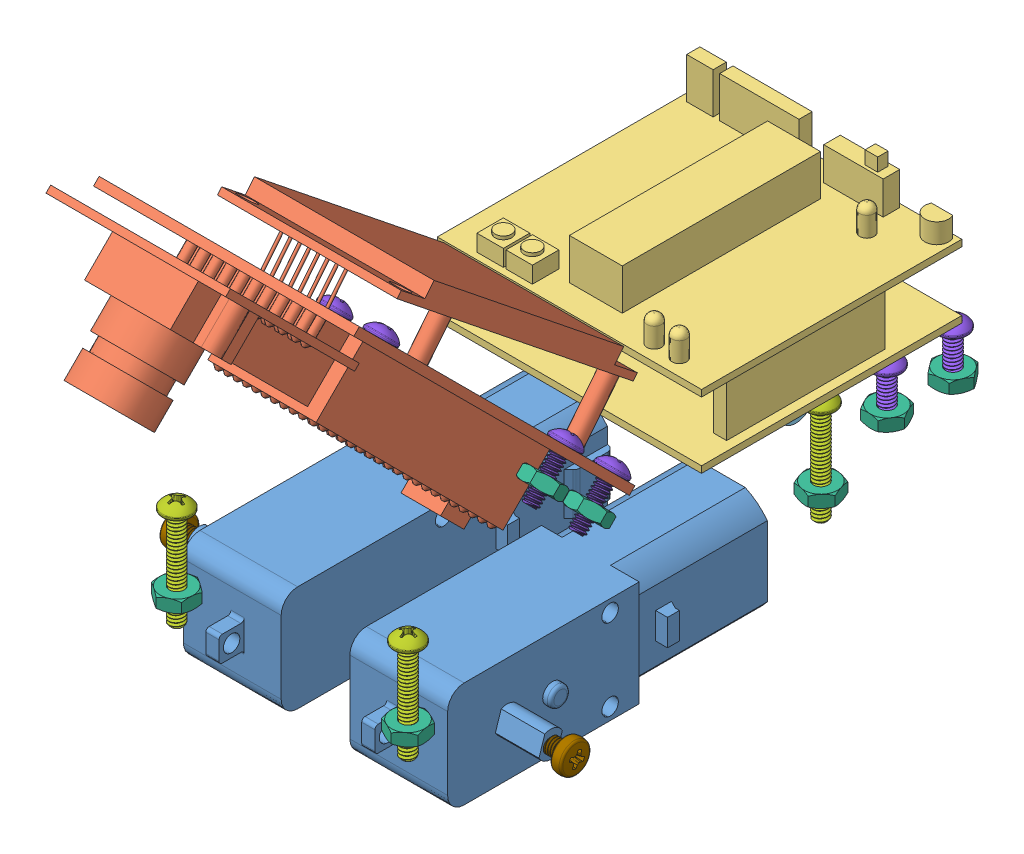
SolidWorks assembly Assembly, configuration Default. Lengths in mm.
Overall size (78.67 116.53 164.64).
47 component instances, 20 part files, 114 mates.
Components (placement in the parent):
- Motor Mount-1: Motor Mount [Default] at (3.175 15.875 -19.05) size (31.75 25.4 76.45) (hidden)
- Wheel 2in-1: Wheel 2in [Default] at (38.1 15.875 -19.05) x (1 0 0) z (0 0.586153 0.810201) size (15.88 53.2 53.2) (hidden)
- TT Motor-1: TT Motor [Default] at (6.604 15.875 -44.45) x (0 0 1) z (1 0 0) size (67.56 20.32 29.46)
- Chassis-1: Chassis [Default] at (3.175 5.3975 -6.35) x (0 0 1) z (-1 0 0) size (73.66 27.3 26.04) (hidden)
- Chassis-2: Chassis [Default] at (-3.175 26.3525 -6.35) x (0 0 1) z (1 0 0) size (73.66 27.3 26.04) (hidden)
- Motor Mount-2: Motor Mount [Default] at (-3.175 15.875 -19.05) x (-1 0 0) z (0 0 1) size (31.75 25.4 76.45) (hidden)
- TT Motor-2: TT Motor [Default] at (-6.604 15.875 -44.45) x (0 0 1) z (-1 0 0) size (67.56 20.32 29.46)
- Cap-1: Cap [Default] at (0 15.875 -76.2) x (0 0 1) z (-1 0 0) size (51.89 44.45 82.55) (hidden)
- Wheel 2in-2: Wheel 2in [Default] at (-38.1 15.875 -19.05) x (-1 0 0) z (0 0.586153 -0.810201) size (15.88 53.2 53.2) (hidden)
- Camera Board-1: Camera Board [Default] at (0 67.4784 -16.4528) x (-1 0 0) z (0 -0.707107 -0.707107) size (50.04 42.04 95)
- PIC Circuit-1: PIC Circuit [Default] at (0 38.1 -81.451) size (50.8 22.86 50.04)
- Front Cap-1: Front Cap [Default] at (0 15.875 -6.35) size (69.85 31.75 19.05) (hidden)
- Top Connector-1: Top Connector [Default] at (22.225 31.75 -82.55) x (0 0 -1) z (1 0 0) size (111.12 30.12 4.76) (hidden)
- Top Connector-2: Top Connector [Default] at (-22.225 31.75 -82.55) x (0 0 -1) z (1 0 0) size (111.12 30.12 4.76) (hidden)
- Tail-1: Tail [Default] at (0 15.875 -88.9) x (-1 0 0) z (0 0 -1) size (82.55 44.45 50.84) (hidden)
- Servo-1: Servo [Default] at (-32.258 16.7255 -105.9248) x (0 0.48481 -0.87462) z (0 -0.87462 -0.48481) size (32.26 29.72 12.19)
- Gear-1: Gear [Default] at (0 15.885 -88.9336) x (-1 0 0) z (0 -0.003163 -0.999995) size (41.34 35.83 44.49) (hidden)
- Servo Single Arm-1: Servo Single Arm [Default] at (-4.826 14.1395 -101.2596) x (0 -0.852015 -0.523518) z (0 -0.523518 0.852015) size (6.86 3.56 18.67)
- 90480A005_Low-Strength Steel Hex Nut-1: 90480A005_Low-Strength Steel Hex Nut [90480A005] at (-22.225 21.0344 -3.175) x (0.428518 0 0.903533) z (0.903533 0 -0.428518) size (6.35 2.87 7.33)
- 91772A113_Passivated 18-8 Stainless Steel Pan Head Phillips Screw-1: 91772A113_Passivated 18-8 Stainless Steel Pan Head Phillips Screw [91772A113] at (-22.225 26.3144 -3.175) x (-0.12802 0 0.991772) z (0 1 0) size (5.56 5.56 21.39)
- 90480A005_Low-Strength Steel Hex Nut-2: 90480A005_Low-Strength Steel Hex Nut [90480A005] at (22.225 21.0344 -3.175) x (0.591115 0 0.806587) z (0.806587 0 -0.591115) size (6.35 2.87 7.33)
- 91772A113_Passivated 18-8 Stainless Steel Pan Head Phillips Screw-2: 91772A113_Passivated 18-8 Stainless Steel Pan Head Phillips Screw [91772A113] at (22.225 26.416 -3.175) x (0.061178 0 0.998127) z (0 1 0) size (5.56 5.56 21.39)
- 91772A113_Passivated 18-8 Stainless Steel Pan Head Phillips Screw-4: 91772A113_Passivated 18-8 Stainless Steel Pan Head Phillips Screw [91772A113] at (22.225 26.416 -82.55) x (1 0 0) z (0 1 0) size (5.56 5.56 21.39)
- 90480A005_Low-Strength Steel Hex Nut-4: 90480A005_Low-Strength Steel Hex Nut [90480A005] at (22.225 21.0344 -82.55) x (0.732529 0 0.680736) z (0.680736 0 -0.732529) size (6.35 2.87 7.33)
- 90480A005_Low-Strength Steel Hex Nut-6: 90480A005_Low-Strength Steel Hex Nut [90480A005] at (-22.225 21.0344 -82.55) x (0.847691 0 0.53049) z (0.53049 0 -0.847691) size (6.35 2.87 7.33)
- 91772A113_Passivated 18-8 Stainless Steel Pan Head Phillips Screw-5: 91772A113_Passivated 18-8 Stainless Steel Pan Head Phillips Screw [91772A113] at (-22.225 26.416 -82.55) x (0.982082 0 -0.188455) z (0 1 0) size (5.56 5.56 21.39)
- 91772A108_Passivated 18-8 Stainless Steel Pan Head Phillips Screw-1: 91772A108_Passivated 18-8 Stainless Steel Pan Head Phillips Screw [91772A108] at (22.225 31.1785 -95.25) x (1 0 0) z (0 1 0) size (5.56 5.56 11.81)
- 90480A005_Low-Strength Steel Hex Nut-8: 90480A005_Low-Strength Steel Hex Nut [90480A005] at (22.225 27.3844 -95.25) x (0.829305 0 0.558796) z (0.558796 0 -0.829305) size (6.35 2.87 7.33)
- 91772A108_Passivated 18-8 Stainless Steel Pan Head Phillips Screw-2: 91772A108_Passivated 18-8 Stainless Steel Pan Head Phillips Screw [91772A108] at (22.225 31.1785 -107.95) x (0.982082 0 -0.188455) z (0 1 0) size (5.56 5.56 11.81)
- 90480A005_Low-Strength Steel Hex Nut-10: 90480A005_Low-Strength Steel Hex Nut [90480A005] at (22.225 27.3844 -107.95) x (0.919754 0 0.392496) z (0.392496 0 -0.919754) size (6.35 2.87 7.33)
- 91772A108_Passivated 18-8 Stainless Steel Pan Head Phillips Screw-4: 91772A108_Passivated 18-8 Stainless Steel Pan Head Phillips Screw [91772A108] at (-22.225 31.1785 -107.95) x (0.918365 0 -0.395734) z (0 1 0) size (5.56 5.56 11.81)
- 90480A005_Low-Strength Steel Hex Nut-12: 90480A005_Low-Strength Steel Hex Nut [90480A005] at (-22.225 27.3844 -107.95) x (0.98274 0 0.184994) z (0.184994 0 -0.98274) size (6.35 2.87 7.33)
- 91772A108_Passivated 18-8 Stainless Steel Pan Head Phillips Screw-6: 91772A108_Passivated 18-8 Stainless Steel Pan Head Phillips Screw [91772A108] at (-22.225 31.1785 -95.25) x (0.8 0 -0.6) z (0 1 0) size (5.56 5.56 11.81)
- 90480A005_Low-Strength Steel Hex Nut-14: 90480A005_Low-Strength Steel Hex Nut [90480A005] at (-22.225 27.3844 -95.25) x (0.998722 0 -0.050547) z (-0.050547 0 -0.998722) size (6.35 2.87 7.33)
- 91772A108_Passivated 18-8 Stainless Steel Pan Head Phillips Screw-8: 91772A108_Passivated 18-8 Stainless Steel Pan Head Phillips Screw [91772A108] at (22.225 50.1914 -30.5967) x (0.699365 -0.505415 -0.505415) z (0 0.707107 -0.707107) size (5.56 5.56 11.81)
- 90480A005_Low-Strength Steel Hex Nut-16: 90480A005_Low-Strength Steel Hex Nut [90480A005] at (22.225 48.676 -29.0813) x (0.979395 -0.142805 -0.142805) z (-0.201956 -0.692537 -0.692537) size (6.35 2.87 7.33)
- 91772A108_Passivated 18-8 Stainless Steel Pan Head Phillips Screw-10: 91772A108_Passivated 18-8 Stainless Steel Pan Head Phillips Screw [91772A108] at (22.225 41.2112 -39.5769) x (0.683739 -0.515995 -0.515995) z (0 0.707107 -0.707107) size (5.56 5.56 11.81)
- 90480A005_Low-Strength Steel Hex Nut-18: 90480A005_Low-Strength Steel Hex Nut [90480A005] at (22.225 39.6958 -38.0615) x (0.974797 -0.157752 -0.157752) z (-0.223096 -0.689285 -0.689285) size (6.35 2.87 7.33)
- 91772A108_Passivated 18-8 Stainless Steel Pan Head Phillips Screw-12: 91772A108_Passivated 18-8 Stainless Steel Pan Head Phillips Screw [91772A108] at (-22.225 50.1914 -30.5967) x (0.634301 -0.546654 -0.546654) z (0 0.707107 -0.707107) size (5.56 5.56 11.81)
- 90480A005_Low-Strength Steel Hex Nut-20: 90480A005_Low-Strength Steel Hex Nut [90480A005] at (-22.225 48.676 -29.0813) x (0.958027 -0.202713 -0.202713) z (-0.286679 -0.677427 -0.677427) size (6.35 2.87 7.33)
- 91772A108_Passivated 18-8 Stainless Steel Pan Head Phillips Screw-14: 91772A108_Passivated 18-8 Stainless Steel Pan Head Phillips Screw [91772A108] at (-22.225 41.2112 -39.5769) x (0.544611 -0.593043 -0.593043) z (0 0.707107 -0.707107) size (5.56 5.56 11.81)
- 90480A005_Low-Strength Steel Hex Nut-22: 90480A005_Low-Strength Steel Hex Nut [90480A005] at (-22.225 39.6958 -38.0615) x (0.920304 -0.276622 -0.276622) z (-0.391203 -0.650753 -0.650753) size (6.35 2.87 7.33)
- 92005A118_Steel Pan Head Phillips Screw-1: 92005A118_Steel Pan Head Phillips Screw [92005A118] at (-32.5125 15.875 -19.05) x (0 0.980077 0.198616) z (-1 0 0) size (6 6 10.57)
- 92005A118_Steel Pan Head Phillips Screw-2: 92005A118_Steel Pan Head Phillips Screw [92005A118] at (32.5125 15.875 -19.05) x (0 -0.392368 -0.919808) z (1 0 0) size (6 6 10.57)
- 91772A086_Passivated 18-8 Stainless Steel Pan Head Phillips Screw-1: 91772A086_Passivated 18-8 Stainless Steel Pan Head Phillips Screw [91772A086] at (-25.9499 9.8763 -93.6036) x (0 -0.608635 -0.79345) z (1 0 0) size (4.24 4.24 27.29)
- 90480A003_Low-Strength Steel Hex Nut-1: 90480A003_Low-Strength Steel Hex Nut [90480A003] at (-23.6538 9.8763 -93.6036) x (0 0.999076 -0.042978) z (0 0.042978 0.999076) size (4.76 1.94 5.5)
- Head-1: Head [Default] at (0 15.875 0) size (69.85 34.93 34.93) (hidden)
Mates (geometry in assembly coordinates):
- Concentric1: concentric anti-aligned: cylinder of Motor Mount-1 through (34.925 15.875 -19.05) axis (-1 0 0) radius 5.3975; cylinder of Wheel 2in-1 through (25.4 15.875 -19.05) axis (1 0 0) radius 4.7625
- Distance1: distance = 3.175 mm anti-aligned: plane of Wheel 2in-1 through (38.1 15.875 -19.05) normal (-1 0 0); plane of Motor Mount-1 through (34.925 15.875 -19.05) normal (1 0 0)
- Coincident2: coincident anti-aligned: plane of Wheel 2in-1 through (25.4 17.053 -21.3003) normal (0 0.308058 0.951368); plane of TT Motor-1 through (33.782 13.6016 -20.1827) normal (0 -0.308058 -0.951368)
- Concentric3: concentric anti-aligned: cylinder of Wheel 2in-1 through (25.4 15.875 -19.05) axis (1 0 0) radius 2.54; cylinder of TT Motor-1 through (33.782 15.875 -19.05) axis (-1 0 0) radius 2.54
- Parallel1: parallel aligned: plane of Motor Mount-1 through (34.925 28.575 -6.35) normal (0 1 0); plane of TT Motor-1 through (25.4 26.035 -44.45) normal (0 1 0)
- Coincident4: coincident anti-aligned: plane of Wheel 2in-1 through (25.4 15.875 -19.05) normal (-1 0 0); plane of TT Motor-1 through (25.4 15.875 -44.45) normal (1 0 0)
- Coincident5: coincident anti-aligned: plane of Motor Mount-1 through (26.035 15.875 -19.05) normal (-1 0 0); plane of Chassis-1 through (26.035 5.3975 -6.35) normal (1 0 0)
- Concentric4: concentric anti-aligned: cylinder of Motor Mount-1 through (34.925 22.225 -73.025) axis (-1 0 0) radius 1.5875; cylinder of Chassis-1 through (0 22.225 -73.025) axis (1 0 0) radius 1.5875
- Concentric5: concentric anti-aligned: cylinder of Motor Mount-1 through (34.925 9.525 -73.025) axis (-1 0 0) radius 1.5875; cylinder of Chassis-1 through (0 9.525 -73.025) axis (1 0 0) radius 1.5875
- Concentric6: concentric anti-aligned: cylinder of Chassis-1 through (0 9.525 -73.025) axis (1 0 0) radius 1.5875; cylinder of Chassis-2 through (0 9.525 -73.025) axis (-1 0 0) radius 1.5875
- Concentric7: concentric anti-aligned: cylinder of Chassis-1 through (0 22.225 -73.025) axis (1 0 0) radius 1.5875; cylinder of Chassis-2 through (0 22.225 -73.025) axis (-1 0 0) radius 1.5875
- Coincident7: coincident anti-aligned: plane of Chassis-1 through (0 5.3975 -6.35) normal (-1 0 0); plane of Chassis-2 through (0 26.3525 -6.35) normal (1 0 0)
- Concentric8: concentric anti-aligned: cylinder of Chassis-2 through (0 22.225 -73.025) axis (-1 0 0) radius 1.5875; cylinder of Motor Mount-2 through (-34.925 22.225 -73.025) axis (1 0 0) radius 1.5875
- Concentric9: concentric anti-aligned: cylinder of Chassis-2 through (0 9.525 -73.025) axis (-1 0 0) radius 1.5875; cylinder of Motor Mount-2 through (-34.925 9.525 -73.025) axis (1 0 0) radius 1.5875
- Coincident8: coincident anti-aligned: plane of Chassis-2 through (-3.175 26.3525 -6.35) normal (-1 0 0); plane of Motor Mount-2 through (-3.175 15.875 -19.05) normal (1 0 0)
- Concentric10: concentric aligned: cylinder of Motor Mount-2 through (-34.925 15.875 -19.05) axis (1 0 0) radius 5.3975; cylinder of TT Motor-2 through (-33.782 15.875 -19.05) axis (1 0 0) radius 2.54
- Parallel2: parallel aligned: plane of Motor Mount-2 through (-34.925 28.575 -6.35) normal (0 1 0); plane of TT Motor-2 through (-25.4 26.035 -44.45) normal (0 1 0)
- Coincident11: coincident anti-aligned: plane of Chassis-2 through (-3.175 26.3525 -6.35) normal (-1 0 0); plane of Cap-1 through (-3.175 15.875 -63.5) normal (1 0 0)
- Coincident12: coincident anti-aligned: plane of Chassis-2 through (-3.175 29.5275 -6.35) normal (0 1 0); plane of Cap-1 through (0 29.5275 -63.5) normal (0 -1 0)
- Coincident13: coincident anti-aligned: plane of Motor Mount-2 through (-34.925 3.175 -76.2) normal (0 0 -1); plane of Cap-1 through (0 15.875 -76.2) normal (0 0 1)
- Coincident14: coincident anti-aligned: plane of TT Motor-2 through (-33.782 18.1484 -20.1827) normal (0 0.308058 -0.951368); plane of Wheel 2in-2 through (-25.4 14.697 -21.3003) normal (0 -0.308058 0.951368)
- Concentric11: concentric anti-aligned: cylinder of Motor Mount-2 through (-34.925 15.875 -19.05) axis (1 0 0) radius 5.3975; cylinder of Wheel 2in-2 through (-25.4 15.875 -19.05) axis (-1 0 0) radius 4.7625
- Coincident15: coincident anti-aligned: plane of TT Motor-2 through (-25.4 15.875 -44.45) normal (-1 0 0); plane of Wheel 2in-2 through (-25.4 15.875 -19.05) normal (1 0 0)
- Coincident16: coincident: line of Chassis-1 through (0 22.479 -6.35) axis (0 1 0)
- Coincident17: coincident anti-aligned: plane of Camera Board-1 through (0 67.4784 -16.4528) normal (-1 0 0)
- Coincident18: coincident aligned: plane of PIC Circuit-1 through (0 38.1 -81.451) normal (1 0 0)
- Distance2: distance = 3.175 mm anti-aligned: plane of Motor Mount-2 through (-34.925 15.875 -19.05) normal (-1 0 0); plane of Wheel 2in-2 through (-38.1 15.875 -19.05) normal (1 0 0)
- Coincident19: coincident anti-aligned: plane of Motor Mount-1 through (34.925 28.575 -6.35) normal (0 0 1); plane of Front Cap-1 through (0 15.875 -6.35) normal (0 0 -1)
- Coincident20: coincident anti-aligned: plane of Chassis-1 through (3.175 5.3975 -6.35) normal (1 0 0); plane of Front Cap-1 through (3.175 15.875 -19.05) normal (-1 0 0)
- Coincident21: coincident anti-aligned: plane of Chassis-1 through (3.175 2.2225 -6.35) normal (0 -1 0); plane of Front Cap-1 through (0 2.2225 -19.05) normal (0 1 0)
- Concentric12: concentric anti-aligned: cylinder of Cap-1 through (22.225 11.43 -82.55) axis (0 1 0) radius 1.5875; cylinder of Top Connector-1 through (22.225 34.925 -82.55) axis (0 -1 0) radius 1.5875
- Concentric13: concentric anti-aligned: cylinder of Front Cap-1 through (22.225 11.43 -3.175) axis (0 1 0) radius 1.5875; cylinder of Top Connector-1 through (22.225 34.925 -3.175) axis (0 -1 0) radius 1.5875
- Coincident22: coincident anti-aligned: plane of Front Cap-1 through (0 31.75 -19.05) normal (0 1 0); plane of Top Connector-1 through (22.225 31.75 -82.55) normal (0 -1 0)
- Concentric14: concentric anti-aligned: cylinder of Camera Board-1 through (22.225 52.8406 -33.2459) axis (0 -0.707107 0.707107) radius 1.651; cylinder of Top Connector-1 through (22.225 25.6714 -6.0766) axis (0 0.707107 -0.707107) radius 1.5875
- Concentric15: concentric anti-aligned: cylinder of Camera Board-1 through (22.225 43.8604 -42.2261) axis (0 -0.707107 0.707107) radius 1.651; cylinder of Top Connector-1 through (22.225 16.6911 -15.0569) axis (0 0.707107 -0.707107) radius 1.5875
- Coincident23: coincident anti-aligned: plane of Camera Board-1 through (0 67.4784 -16.4528) normal (0 -0.707107 0.707107); plane of Top Connector-1 through (19.8438 16.5656 -67.3656) normal (0 0.707107 -0.707107)
- Concentric16: concentric anti-aligned: cylinder of Cap-1 through (-22.225 11.43 -82.55) axis (0 1 0) radius 1.5875; cylinder of Top Connector-2 through (-22.225 34.925 -82.55) axis (0 -1 0) radius 1.5875
- Concentric17: concentric anti-aligned: cylinder of Front Cap-1 through (-22.225 11.43 -3.175) axis (0 1 0) radius 1.5875; cylinder of Top Connector-2 through (-22.225 34.925 -3.175) axis (0 -1 0) radius 1.5875
- Coincident24: coincident anti-aligned: plane of Cap-1 through (0 31.75 -63.5) normal (0 1 0); plane of Top Connector-2 through (-22.225 31.75 -82.55) normal (0 -1 0)
- Coincident25: coincident anti-aligned: plane of Cap-1 through (0 15.875 -88.9) normal (0 0 -1); plane of Tail-1 through (0 15.875 -88.9) normal (0 0 1)
- Coincident26: coincident aligned: plane of Cap-1 through (-41.275 15.875 -76.2) normal (-1 0 0); plane of Tail-1 through (-41.275 -6.35 -88.9) normal (-1 0 0)
- Tangent1: tangent: line of Cap-1 through (-34.925 31.75 -88.9) axis (1 0 0); face of Tail-1
- Coincident27: coincident anti-aligned: plane of Front Cap-1 through (0 0 0) normal (0 -1 0)
- Coincident28: coincident aligned: plane of Front Cap-1 through (0 15.875 0) normal (0 0 1)
- Coincident30: coincident anti-aligned: plane of Tail-1 through (-16.51 4.3712 -99.7044) normal (0 0.48481 -0.87462); plane of Servo-1 through (-9.906 5.8524 -98.8833) normal (0 -0.48481 0.87462)
- Coincident31: coincident anti-aligned: plane of Tail-1 through (-16.51 16.5158 -92.9725) normal (0 -0.87462 -0.48481); plane of Servo-1 through (-9.906 16.5158 -92.9725) normal (0 0.87462 0.48481)
- Coincident32: coincident anti-aligned: plane of Tail-1 through (-16.51 15.875 -88.9) normal (1 0 0); plane of Servo-1 through (-16.51 9.8763 -93.6036) normal (-1 0 0)
- Concentric18: concentric aligned: cylinder of Tail-1 through (-41.2761 5.2681 -92.075) axis (1 0 0) radius 1.5875; cylinder of Gear-1 through (-41.2761 5.2681 -92.075) axis (1 0 0) radius 1.5875
- Coincident33: coincident anti-aligned: plane of Tail-1 through (-3.175 -3.175 -139.7) normal (1 0 0); plane of Gear-1 through (-3.175 -3.3256 -139.6731) normal (-1 0 0)
- Concentric19: concentric aligned: cylinder of Servo-1 through (-2.54 14.1395 -101.2596) axis (-1 0 0) radius 2.413; cylinder of Servo Single Arm-1 through (-1.27 14.1395 -101.2596) axis (-1 0 0) radius 2.286
- Coincident34: coincident anti-aligned: plane of Servo-1 through (-2.54 14.1395 -101.2596) normal (1 0 0); plane of Servo Single Arm-1 through (-2.54 14.1395 -101.2596) normal (-1 0 0)
- Distance3: distance = 9.525 mm: cylinder of Gear-1 through (0 12.656 -109.5102) axis (1 0 0) radius 0.8047; cylinder of Servo Single Arm-1 through (-4.826 21.4531 -113.1623) axis (1 0 0) radius 0.508
- Coincident35: coincident anti-aligned: plane of PIC Circuit-1 through (0 38.1 -81.451) normal (0 -1 0); plane of Top Connector-1 through (19.8438 38.1 -82.55) normal (0 1 0)
- Coincident36: coincident anti-aligned: plane of PIC Circuit-1 through (-25.4 39.37 -56.432) normal (0 0 1); plane of Top Connector-1 through (19.8438 31.75 -56.432) normal (0 0 -1)
- Concentric21: concentric anti-aligned: cylinder of Top Connector-2 through (-22.225 34.925 -3.175) axis (0 -1 0) radius 1.5875; cylinder of 91772A110_Passivated 18-8 Stainless Steel Pan Head Phillips Screw-1 through (-22.225 37.0313 -3.175) axis (0 1 0) radius 1.4224
- Coincident38: coincident anti-aligned: plane of Front Cap-1 through (-26.1937 22.225 -6.35) normal (0 -1 0); plane of 90480A005_Low-Strength Steel Hex Nut-1 through (-25.2418 22.225 -5.2582) normal (0 1 0)
- Concentric22: concentric anti-aligned: cylinder of Top Connector-2 through (-22.225 34.925 -3.175) axis (0 -1 0) radius 1.5875; cylinder of 91772A113_Passivated 18-8 Stainless Steel Pan Head Phillips Screw-1 through (-22.225 36.8554 -3.175) axis (0 1 0) radius 1.4224
- Tangent2: tangent anti-aligned: plane of Top Connector-2 through (-22.225 34.925 -82.55) normal (0 1 0); torus of 91772A113_Passivated 18-8 Stainless Steel Pan Head Phillips Screw-1
- Concentric23: concentric aligned: cylinder of 90480A005_Low-Strength Steel Hex Nut-1 through (-22.225 19.8438 -3.175) axis (0 1 0) radius 1.4224; cylinder of 91772A113_Passivated 18-8 Stainless Steel Pan Head Phillips Screw-1 through (-22.225 36.8554 -3.175) axis (0 1 0) radius 1.4224
- Concentric24: concentric aligned: cylinder of 90480A005_Low-Strength Steel Hex Nut-2 through (22.225 19.8438 -3.175) axis (0 1 0) radius 1.4224; cylinder of 91772A113_Passivated 18-8 Stainless Steel Pan Head Phillips Screw-2 through (22.225 36.957 -3.175) axis (0 1 0) radius 1.4224
- Coincident39: coincident anti-aligned: plane of Front Cap-1 through (26.1937 22.225 -6.35) normal (0 -1 0); plane of 90480A005_Low-Strength Steel Hex Nut-2 through (18.8697 22.225 -4.6523) normal (0 1 0)
- Concentric25: concentric anti-aligned: cylinder of Top Connector-1 through (22.225 34.925 -3.175) axis (0 -1 0) radius 1.5875; cylinder of 91772A113_Passivated 18-8 Stainless Steel Pan Head Phillips Screw-2 through (22.225 36.957 -3.175) axis (0 1 0) radius 1.4224
- Coincident40: coincident anti-aligned: plane of Top Connector-1 through (22.225 34.925 -82.55) normal (0 1 0); plane of 91772A113_Passivated 18-8 Stainless Steel Pan Head Phillips Screw-2 through (23.6447 34.925 -3.262) normal (0 -1 0)
- Coincident41: coincident anti-aligned: plane of Top Connector-1 through (22.225 34.925 -82.55) normal (0 1 0); plane of 91772A113_Passivated 18-8 Stainless Steel Pan Head Phillips Screw-4 through (22.225 34.925 -83.9724) normal (0 -1 0)
- Concentric27: concentric anti-aligned: cylinder of Top Connector-1 through (22.225 34.925 -82.55) axis (0 -1 0) radius 1.5875; cylinder of 91772A113_Passivated 18-8 Stainless Steel Pan Head Phillips Screw-4 through (22.225 36.957 -82.55) axis (0 1 0) radius 1.4224
- Concentric28: concentric aligned: cylinder of 91772A113_Passivated 18-8 Stainless Steel Pan Head Phillips Screw-4 through (22.225 36.957 -82.55) axis (0 1 0) radius 1.4224; cylinder of 90480A005_Low-Strength Steel Hex Nut-4 through (22.225 19.8438 -82.55) axis (0 1 0) radius 1.4224
- Coincident42: coincident anti-aligned: plane of Cap-1 through (26.1937 22.225 -76.2) normal (0 -1 0); plane of 90480A005_Low-Strength Steel Hex Nut-4 through (18.6514 22.225 -83.3685) normal (0 1 0)
- Concentric29: concentric aligned: cylinder of 90480A005_Low-Strength Steel Hex Nut-6 through (-22.225 19.8438 -82.55) axis (0 1 0) radius 1.4224; cylinder of 91772A113_Passivated 18-8 Stainless Steel Pan Head Phillips Screw-5 through (-22.225 36.957 -82.55) axis (0 1 0) radius 1.4224
- Coincident43: coincident anti-aligned: plane of Top Connector-2 through (-22.225 34.925 -82.55) normal (0 1 0); plane of 91772A113_Passivated 18-8 Stainless Steel Pan Head Phillips Screw-5 through (-22.4931 34.925 -83.9469) normal (0 -1 0)
- Concentric30: concentric anti-aligned: cylinder of Top Connector-2 through (-22.225 34.925 -82.55) axis (0 -1 0) radius 1.5875; cylinder of 91772A113_Passivated 18-8 Stainless Steel Pan Head Phillips Screw-5 through (-22.225 36.957 -82.55) axis (0 1 0) radius 1.4224
- Coincident44: coincident anti-aligned: plane of Cap-1 through (-26.1937 22.225 -76.2) normal (0 -1 0); plane of 90480A005_Low-Strength Steel Hex Nut-6 through (-25.8889 22.225 -82.6804) normal (0 1 0)
- Coincident45: coincident anti-aligned: plane of Top Connector-1 through (22.225 34.925 -82.55) normal (0 1 0); plane of 91772A108_Passivated 18-8 Stainless Steel Pan Head Phillips Screw-1 through (22.225 34.925 -96.6724) normal (0 -1 0)
- Concentric32: concentric aligned: cylinder of Top Connector-1 through (22.225 31.75 -95.25) axis (0 1 0) radius 1.5875; cylinder of 91772A108_Passivated 18-8 Stainless Steel Pan Head Phillips Screw-1 through (22.225 36.957 -95.25) axis (0 1 0) radius 1.4224
- Concentric33: concentric aligned: cylinder of 91772A108_Passivated 18-8 Stainless Steel Pan Head Phillips Screw-1 through (22.225 36.957 -95.25) axis (0 1 0) radius 1.4224; cylinder of 90480A005_Low-Strength Steel Hex Nut-8 through (22.225 26.1937 -95.25) axis (0 1 0) radius 1.4224
- Tangent7: tangent: plane of assembly; face of Tail-1; plane of 90480A005_Low-Strength Steel Hex Nut-8 through (18.5676 28.575 -95.504) normal (0 1 0)
- Concentric34: concentric aligned: cylinder of 91772A108_Passivated 18-8 Stainless Steel Pan Head Phillips Screw-2 through (22.225 36.957 -107.95) axis (0 1 0) radius 1.4224; cylinder of 90480A005_Low-Strength Steel Hex Nut-10 through (22.225 26.1937 -107.95) axis (0 1 0) radius 1.4224
- Coincident47: coincident anti-aligned: plane of Top Connector-1 through (22.225 34.925 -82.55) normal (0 1 0); plane of 91772A108_Passivated 18-8 Stainless Steel Pan Head Phillips Screw-2 through (21.9569 34.925 -109.3469) normal (0 -1 0)
- Concentric35: concentric aligned: cylinder of Top Connector-1 through (22.225 31.75 -107.95) axis (0 1 0) radius 1.5875; cylinder of 91772A108_Passivated 18-8 Stainless Steel Pan Head Phillips Screw-2 through (22.225 36.957 -107.95) axis (0 1 0) radius 1.4224
- Tangent8: tangent: plane of assembly; face of Tail-1; plane of 90480A005_Low-Strength Steel Hex Nut-10 through (18.5853 28.575 -107.5102) normal (0 1 0)
- Concentric37: concentric aligned: cylinder of 91772A108_Passivated 18-8 Stainless Steel Pan Head Phillips Screw-4 through (-22.225 36.957 -107.95) axis (0 1 0) radius 1.4224; cylinder of 90480A005_Low-Strength Steel Hex Nut-12 through (-22.225 26.1937 -107.95) axis (0 1 0) radius 1.4224
- Coincident48: coincident anti-aligned: plane of Top Connector-2 through (-22.225 34.925 -82.55) normal (0 1 0); plane of 91772A108_Passivated 18-8 Stainless Steel Pan Head Phillips Screw-4 through (-22.7879 34.925 -109.2563) normal (0 -1 0)
- Concentric38: concentric aligned: cylinder of Top Connector-2 through (-22.225 31.75 -107.95) axis (0 1 0) radius 1.5875; cylinder of 91772A108_Passivated 18-8 Stainless Steel Pan Head Phillips Screw-4 through (-22.225 36.957 -107.95) axis (0 1 0) radius 1.4224
- Tangent9: tangent: plane of assembly; face of Tail-1; plane of 90480A005_Low-Strength Steel Hex Nut-12 through (-25.6843 28.575 -106.7359) normal (0 1 0)
- Concentric40: concentric aligned: cylinder of 91772A108_Passivated 18-8 Stainless Steel Pan Head Phillips Screw-6 through (-22.225 36.957 -95.25) axis (0 1 0) radius 1.4224; cylinder of 90480A005_Low-Strength Steel Hex Nut-14 through (-22.225 26.1937 -95.25) axis (0 1 0) radius 1.4224
- Coincident49: coincident anti-aligned: plane of Top Connector-2 through (-22.225 34.925 -82.55) normal (0 1 0); plane of 91772A108_Passivated 18-8 Stainless Steel Pan Head Phillips Screw-6 through (-23.0784 34.925 -96.3879) normal (0 -1 0)
- Concentric41: concentric aligned: cylinder of Top Connector-2 through (-22.225 31.75 -95.25) axis (0 1 0) radius 1.5875; cylinder of 91772A108_Passivated 18-8 Stainless Steel Pan Head Phillips Screw-6 through (-22.225 36.957 -95.25) axis (0 1 0) radius 1.4224
- Tangent10: tangent: plane of assembly; face of Tail-1; plane of 90480A005_Low-Strength Steel Hex Nut-14 through (-25.3033 28.575 -93.2588) normal (0 1 0)
- Concentric43: concentric aligned: cylinder of 91772A108_Passivated 18-8 Stainless Steel Pan Head Phillips Screw-8 through (22.225 54.2775 -34.6827) axis (0 0.707107 -0.707107) radius 1.4224; cylinder of 90480A005_Low-Strength Steel Hex Nut-16 through (22.225 47.8341 -28.2394) axis (0 0.707107 -0.707107) radius 1.4224
- Coincident50: coincident anti-aligned: plane of Camera Board-1 through (0 68.5561 -17.5304) normal (0 0.707107 -0.707107); plane of 91772A108_Passivated 18-8 Stainless Steel Pan Head Phillips Screw-8 through (21.2083 52.1372 -33.9493) normal (0 -0.707107 0.707107)
- Concentric44: concentric anti-aligned: cylinder of Camera Board-1 through (22.225 52.8406 -33.2459) axis (0 -0.707107 0.707107) radius 1.651; cylinder of 91772A108_Passivated 18-8 Stainless Steel Pan Head Phillips Screw-8 through (22.225 54.2775 -34.6827) axis (0 0.707107 -0.707107) radius 1.4224
- Coincident51: coincident anti-aligned: plane of Top Connector-1 through (19.8438 14.3205 -65.1205) normal (0 -0.707107 0.707107); plane of 90480A005_Low-Strength Steel Hex Nut-16 through (19.4856 51.2408 -28.2003) normal (0 0.707107 -0.707107)
- Concentric46: concentric aligned: cylinder of 91772A108_Passivated 18-8 Stainless Steel Pan Head Phillips Screw-10 through (22.225 45.2972 -43.663) axis (0 0.707107 -0.707107) radius 1.4224; cylinder of 90480A005_Low-Strength Steel Hex Nut-18 through (22.225 38.8539 -37.2196) axis (0 0.707107 -0.707107) radius 1.4224
- Coincident52: coincident anti-aligned: plane of Camera Board-1 through (0 68.5561 -17.5304) normal (0 0.707107 -0.707107); plane of 91772A108_Passivated 18-8 Stainless Steel Pan Head Phillips Screw-10 through (21.187 43.1727 -42.9138) normal (0 -0.707107 0.707107)
- Concentric47: concentric anti-aligned: cylinder of Camera Board-1 through (22.225 43.8604 -42.2261) axis (0 -0.707107 0.707107) radius 1.651; cylinder of 91772A108_Passivated 18-8 Stainless Steel Pan Head Phillips Screw-10 through (22.225 45.2972 -43.663) axis (0 0.707107 -0.707107) radius 1.4224
- Coincident53: coincident anti-aligned: plane of Top Connector-1 through (19.8438 14.3205 -65.1205) normal (0 -0.707107 0.707107); plane of 90480A005_Low-Strength Steel Hex Nut-18 through (19.539 42.302 -37.139) normal (0 0.707107 -0.707107)
- Concentric49: concentric aligned: cylinder of 91772A108_Passivated 18-8 Stainless Steel Pan Head Phillips Screw-12 through (-22.225 54.2775 -34.6827) axis (0 0.707107 -0.707107) radius 1.4224; cylinder of 90480A005_Low-Strength Steel Hex Nut-20 through (-22.225 47.8341 -28.2394) axis (0 0.707107 -0.707107) radius 1.4224
- Coincident54: coincident anti-aligned: plane of Camera Board-1 through (0 68.5561 -17.5304) normal (0 0.707107 -0.707107); plane of 91772A108_Passivated 18-8 Stainless Steel Pan Head Phillips Screw-12 through (-23.3246 52.2026 -33.8838) normal (0 -0.707107 0.707107)
- Concentric50: concentric anti-aligned: cylinder of Camera Board-1 through (-22.225 52.8406 -33.2459) axis (0 -0.707107 0.707107) radius 1.651; cylinder of 91772A108_Passivated 18-8 Stainless Steel Pan Head Phillips Screw-12 through (-22.225 54.2775 -34.6827) axis (0 0.707107 -0.707107) radius 1.4224
- Coincident55: coincident anti-aligned: plane of Top Connector-2 through (-24.6062 14.3205 -65.1205) normal (0 -0.707107 0.707107); plane of 90480A005_Low-Strength Steel Hex Nut-20 through (-24.7412 51.4033 -28.0378) normal (0 0.707107 -0.707107)
- Concentric52: concentric aligned: cylinder of 91772A108_Passivated 18-8 Stainless Steel Pan Head Phillips Screw-14 through (-22.225 45.2972 -43.663) axis (0 0.707107 -0.707107) radius 1.4224; cylinder of 90480A005_Low-Strength Steel Hex Nut-22 through (-22.225 38.8539 -37.2196) axis (0 0.707107 -0.707107) radius 1.4224
- Coincident56: coincident anti-aligned: plane of Camera Board-1 through (0 68.5561 -17.5304) normal (0 0.707107 -0.707107); plane of 91772A108_Passivated 18-8 Stainless Steel Pan Head Phillips Screw-14 through (-23.418 43.3126 -42.7739) normal (0 -0.707107 0.707107)
- Concentric53: concentric anti-aligned: cylinder of Camera Board-1 through (-22.225 43.8604 -42.2261) axis (0 -0.707107 0.707107) radius 1.651; cylinder of 91772A108_Passivated 18-8 Stainless Steel Pan Head Phillips Screw-14 through (-22.225 45.2972 -43.663) axis (0 0.707107 -0.707107) radius 1.4224
- Coincident57: coincident anti-aligned: plane of Top Connector-2 through (-24.6062 14.3205 -65.1205) normal (0 -0.707107 0.707107); plane of 90480A005_Low-Strength Steel Hex Nut-22 through (-24.4299 42.6088 -36.8323) normal (0 0.707107 -0.707107)
- Concentric58: concentric aligned: cylinder of Wheel 2in-2 through (-25.4 15.875 -19.05) axis (-1 0 0) radius 2.54; cylinder of 92005A118_Steel Pan Head Phillips Screw-1 through (-36.5125 15.875 -19.05) axis (-1 0 0) radius 1.5
- Coincident58: coincident anti-aligned: plane of Wheel 2in-2 through (-36.5125 15.875 -19.05) normal (-1 0 0); plane of 92005A118_Steel Pan Head Phillips Screw-1 through (-36.5125 15.389 -16.6519) normal (1 0 0)
- Concentric59: concentric aligned: cylinder of Wheel 2in-1 through (25.4 15.875 -19.05) axis (1 0 0) radius 2.54; cylinder of 92005A118_Steel Pan Head Phillips Screw-2 through (36.5125 15.875 -19.05) axis (1 0 0) radius 1.5
- Coincident59: coincident anti-aligned: plane of Wheel 2in-1 through (36.5125 15.875 -19.05) normal (1 0 0); plane of 92005A118_Steel Pan Head Phillips Screw-2 through (36.5125 13.6243 -18.0899) normal (-1 0 0)
- Concentric60: concentric anti-aligned: cylinder of Servo-1 through (-13.97 9.8763 -93.6036) axis (-1 0 0) radius 1.27; cylinder of 91772A086_Passivated 18-8 Stainless Steel Pan Head Phillips Screw-1 through (-12.4498 9.8763 -93.6036) axis (1 0 0) radius 1.0922
- Tangent13: tangent anti-aligned: plane of Servo-1 through (-13.97 9.8763 -93.6036) normal (1 0 0); torus of 91772A086_Passivated 18-8 Stainless Steel Pan Head Phillips Screw-1
- Coincident60: coincident anti-aligned: plane of Tail-1 through (-22.86 15.875 -88.9) normal (-1 0 0); plane of 90480A003_Low-Strength Steel Hex Nut-1 through (-22.86 7.4381 -94.8748) normal (1 0 0)
- Concentric61: concentric anti-aligned: cylinder of 91772A086_Passivated 18-8 Stainless Steel Pan Head Phillips Screw-1 through (-12.4498 9.8763 -93.6036) axis (1 0 0) radius 1.0922; circle of 90480A003_Low-Strength Steel Hex Nut-1
- Coincident61: coincident aligned: plane of Front Cap-1 through (34.925 15.875 -19.05) normal (1 0 0); plane of Head-1 through (34.925 0 3.175) normal (1 0 0)
- Coincident62: coincident anti-aligned: plane of Front Cap-1 through (0 15.875 0) normal (0 0 1); plane of Head-1 through (0 15.875 0) normal (0 0 -1)
- Coincident63: coincident aligned: plane of Top Connector-1 through (22.225 34.925 -82.55) normal (0 1 0); plane of Head-1 through (0 34.925 3.175) normal (0 1 0)
